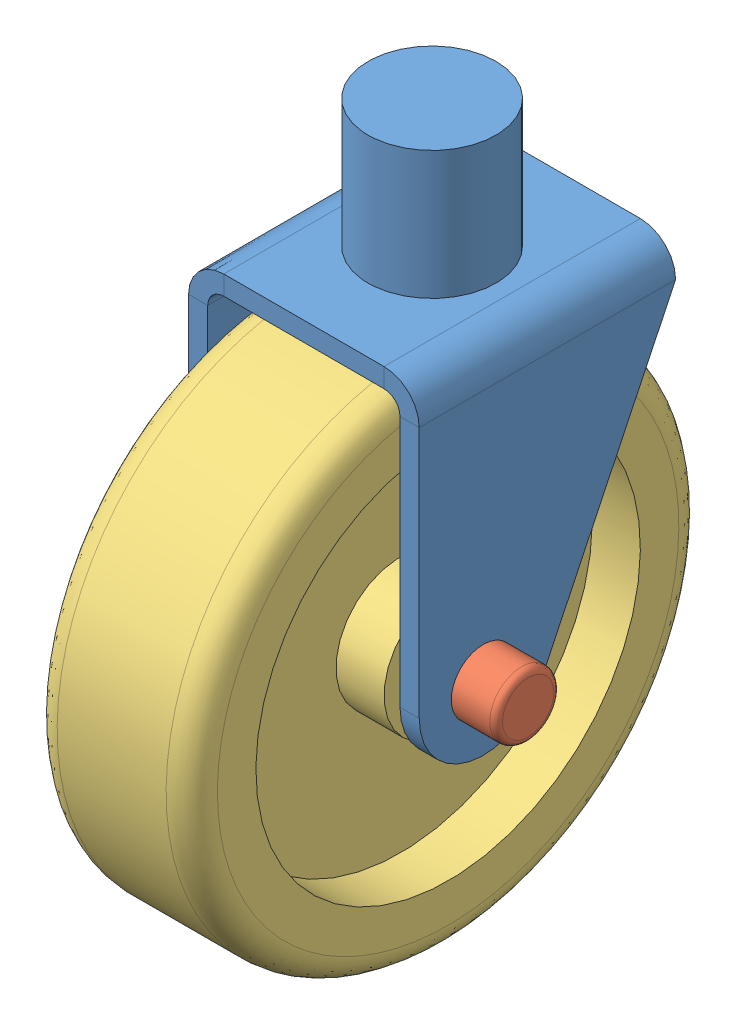
SolidWorks assembly Front Wheel, configuration Default. Lengths in mm.
Overall size (127 266.82 205.91).
3 component instances, 3 part files, 5 mates.
Components (placement in the parent):
- FW Support-2: FW Support [Default] at (46.0725 -79.0572 215.9289) size (91.44 189.99 101.6)
- FW Shaft-2: FW Shaft [Default] at (46.0725 -20.6372 241.3289) size (127 31.75 31.75)
- FW Wheel-2: FW Wheel [Default] at (46.0725 -20.6372 241.3289) x (1 0 0) z (0 -0.013412 -0.99991) size (63.5 203.2 203.2)
Mates (geometry in assembly coordinates):
- Coincident1: coincident anti-aligned: circle of FW Support-2; cylinder of FW Shaft-2 through (-17.4275 -20.6372 241.3289) axis (-1 0 0) radius 12.7
- Concentric1: concentric anti-aligned: cylinder of FW Support-2 through (0.3525 -20.6372 241.3289) axis (1 0 0) radius 12.7; cylinder of FW Shaft-2 through (-17.4275 -20.6372 241.3289) axis (-1 0 0) radius 12.7
- Width1: width anti-aligned: plane of FW Support-2 through (91.7925 -79.0572 266.7289) normal (1 0 0); plane of FW Support-2 through (0.3525 -79.0572 266.7289) normal (-1 0 0); plane of FW Shaft-2 through (-17.4275 -7.9372 241.3289) normal (-1 0 0); plane of FW Shaft-2 through (109.5725 -20.6372 241.3289) normal (1 0 0)
- Concentric2: concentric anti-aligned: cylinder of FW Shaft-2 through (-17.4275 -20.6372 241.3289) axis (-1 0 0) radius 15.875; cylinder of FW Wheel-2 through (14.3225 -20.6372 241.3289) axis (1 0 0) radius 15.875
- Width2: width anti-aligned: plane of FW Support-2 through (0.3525 -79.0572 266.7289) normal (-1 0 0); plane of FW Support-2 through (91.7925 -79.0572 266.7289) normal (1 0 0); plane of FW Wheel-2 through (77.8225 -96.1009 242.3411) normal (1 0 0); plane of FW Wheel-2 through (14.3225 -96.1009 242.3411) normal (-1 0 0)
